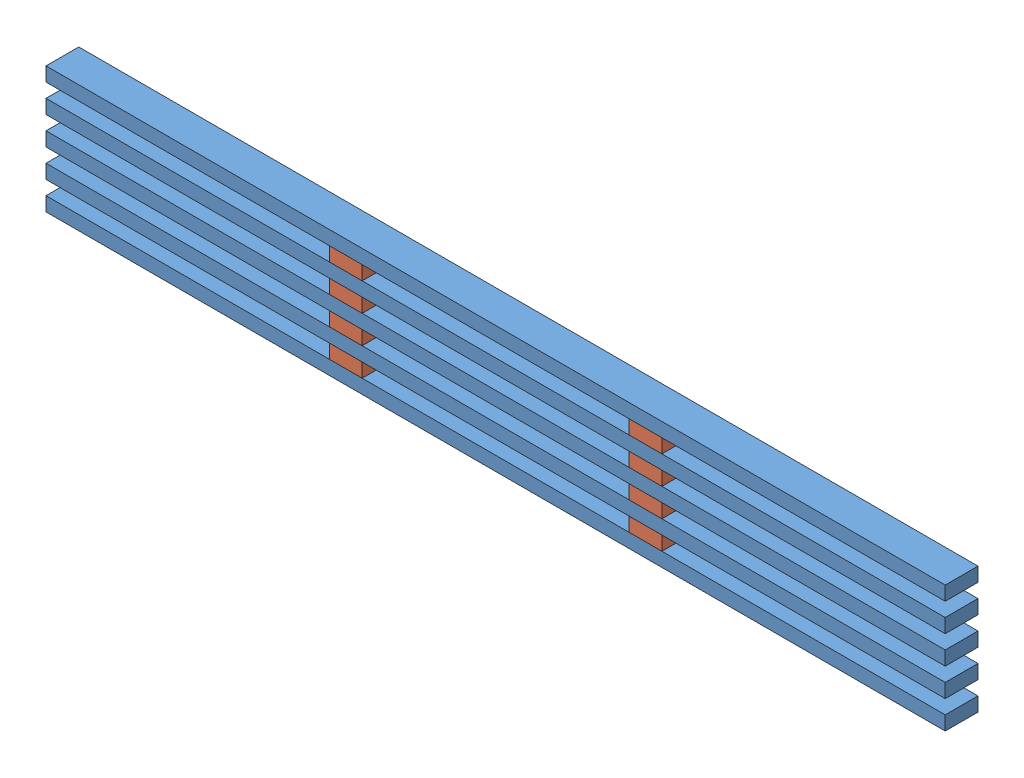
SolidWorks assembly 18x4_female_post, configuration Default. Lengths in mm.
Overall size (2438.4 342.9 88.9).
15 component instances, 2 part files, 18 mates.
Components (placement in the parent):
- 6x4_female_post-1: 6x4_female_post [Default] at (1617.4053 951.3945 1716.6403) size (2438.4 114.3 88.9)
  - 2x4-1: 2x4 [Default] at (-589.9165 1681.5327 2385.3688) size (2438.4 38.1 88.9)
  - 4x4x2_gusset-1: 4x4x2_gusset [Default] at (178.4335 1719.6327 2385.3688) size (88.9 38.1 88.9)
  - 4x4x2_gusset-2: 4x4x2_gusset [Default] at (991.2335 1719.6327 2385.3688) size (88.9 38.1 88.9)
  - 2x4-2: 2x4 [Default] at (-589.9165 1757.7327 2385.3688) size (2438.4 38.1 88.9)
- 6x4_female_post-2: 6x4_female_post [Default] at (1617.4053 1103.7945 1716.6403) size (2438.4 114.3 88.9)
  - 2x4-1: 2x4 [Default] at (-589.9165 1681.5327 2385.3688) size (2438.4 38.1 88.9)
  - 4x4x2_gusset-1: 4x4x2_gusset [Default] at (178.4335 1719.6327 2385.3688) size (88.9 38.1 88.9)
  - 4x4x2_gusset-2: 4x4x2_gusset [Default] at (991.2335 1719.6327 2385.3688) size (88.9 38.1 88.9)
  - 2x4-2: 2x4 [Default] at (-589.9165 1757.7327 2385.3688) size (2438.4 38.1 88.9)
- 4x4x2_gusset-1: 4x4x2_gusset [Default] at (1795.8388 2747.2272 4102.0091) size (88.9 38.1 88.9)
- 4x4x2_gusset-2: 4x4x2_gusset [Default] at (2608.6388 2747.2272 4102.0091) size (88.9 38.1 88.9)
- 2x4-1: 2x4 [Default] at (1027.4888 2937.7272 4102.0091) size (2438.4 38.1 88.9)
- 4x4x2_gusset-3: 4x4x2_gusset [Default] at (1795.8388 2899.6272 4102.0091) size (88.9 38.1 88.9)
- 4x4x2_gusset-4: 4x4x2_gusset [Default] at (2608.6388 2899.6272 4102.0091) size (88.9 38.1 88.9)
Mates (geometry in assembly coordinates):
- Coincident1: coincident: plane of 6x4_female_post-1/4x4x2_gusset-2 through (2697.5388 2709.1272 4102.0091) normal (1 0 0); plane of 4x4x2_gusset-2 through (2697.5388 2785.3272 4102.0091) normal (1 0 0)
- Coincident2: coincident: plane of 6x4_female_post-1/2x4-2 through (1027.4888 2747.2272 4190.9091) normal (0 0 1); plane of 4x4x2_gusset-2 through (2608.6388 2785.3272 4190.9091) normal (0 0 1)
- Coincident3: coincident: plane of 6x4_female_post-2/4x4x2_gusset-2 through (2697.5388 2861.5272 4102.0091) normal (1 0 0); plane of 4x4x2_gusset-2 through (2697.5388 2785.3272 4102.0091) normal (1 0 0)
- Coincident4: coincident: plane of 6x4_female_post-2/4x4x2_gusset-2 through (2608.6388 2861.5272 4190.9091) normal (0 0 1); plane of 4x4x2_gusset-2 through (2608.6388 2785.3272 4190.9091) normal (0 0 1)
- Coincident5: coincident: plane of 6x4_female_post-2/4x4x2_gusset-1 through (1795.8388 2861.5272 4190.9091) normal (0 0 1); plane of 4x4x2_gusset-1 through (1795.8388 2785.3272 4190.9091) normal (0 0 1)
- Coincident6: coincident: plane of 6x4_female_post-2/4x4x2_gusset-1 through (1795.8388 2861.5272 4102.0091) normal (-1 0 0); plane of 4x4x2_gusset-1 through (1795.8388 2785.3272 4102.0091) normal (-1 0 0)
- Coincident7: coincident: plane of 6x4_female_post-1/2x4-2 through (1027.4888 2747.2272 4102.0091) normal (0 1 0); plane of 4x4x2_gusset-1 through (1795.8388 2747.2272 4102.0091) normal (0 -1 0)
- Coincident8: coincident: plane of 6x4_female_post-1/2x4-2 through (1027.4888 2747.2272 4102.0091) normal (0 1 0); plane of 4x4x2_gusset-2 through (2608.6388 2747.2272 4102.0091) normal (0 -1 0)
- Coincident9: coincident: plane of 6x4_female_post-2/2x4-1 through (1027.4888 2785.3272 4102.0091) normal (0 -1 0); plane of 4x4x2_gusset-2 through (2608.6388 2785.3272 4102.0091) normal (0 1 0)
- Coincident10: coincident: plane of 6x4_female_post-2/2x4-2 through (1027.4888 2899.6272 4102.0091) normal (-1 0 0); plane of 2x4-1 through (1027.4888 3515.9829 4102.0091) normal (-1 0 0)
- Coincident11: coincident: plane of 6x4_female_post-2/2x4-2 through (1027.4888 2899.6272 4102.0091) normal (0 0 -1); plane of 2x4-1 through (1027.4888 3515.9829 4102.0091) normal (0 0 -1)
- Coincident12: coincident: plane of 6x4_female_post-2/4x4x2_gusset-2 through (2608.6388 2861.5272 4102.0091) normal (-1 0 0); plane of 4x4x2_gusset-4 through (2608.6388 3272.9746 4102.0091) normal (-1 0 0)
- Coincident13: coincident: plane of 6x4_female_post-2/2x4-2 through (1027.4888 2899.6272 4102.0091) normal (0 0 -1); plane of 4x4x2_gusset-4 through (2608.6388 2937.7272 4102.0091) normal (0 0 -1)
- Coincident14: coincident: plane of 6x4_female_post-2/2x4-2 through (1027.4888 2899.6272 4102.0091) normal (0 1 0); plane of 4x4x2_gusset-4 through (2608.6388 2899.6272 4102.0091) normal (0 -1 0)
- Coincident15: coincident: plane of 6x4_female_post-2/2x4-2 through (1027.4888 2899.6272 4102.0091) normal (0 1 0); plane of 4x4x2_gusset-3 through (1795.8388 2899.6272 4102.0091) normal (0 -1 0)
- Coincident16: coincident: plane of 6x4_female_post-2/2x4-2 through (1027.4888 2899.6272 4102.0091) normal (0 0 -1); plane of 4x4x2_gusset-3 through (1795.8388 2937.7272 4102.0091) normal (0 0 -1)
- Coincident17: coincident: plane of 6x4_female_post-2/4x4x2_gusset-1 through (1795.8388 2861.5272 4102.0091) normal (-1 0 0); plane of 4x4x2_gusset-3 through (1795.8388 2937.7272 4102.0091) normal (-1 0 0)
- Coincident18: coincident: plane of 2x4-1 through (1027.4888 2937.7272 4102.0091) normal (0 -1 0); plane of 4x4x2_gusset-3 through (1795.8388 2937.7272 4102.0091) normal (0 1 0)
